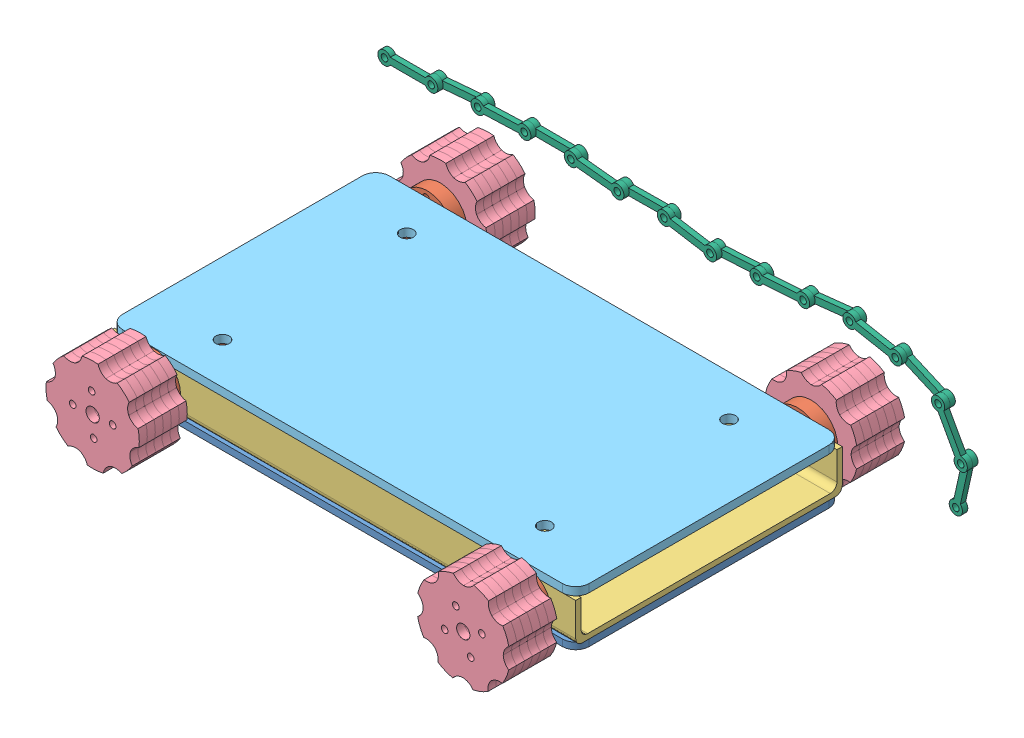
SolidWorks assembly robot, configuration Default. Lengths in mm.
Overall size (444.12 104.35 322.3).
44 component instances, 6 part files, 80 mates.
Components (placement in the parent):
- base-1: base [Default] at (85.4392 139.2891 312.3541) x (0 0 1) z (0 1 0) size (200 350 5)
- shaft-1: shaft [Default] at (-39.5608 161.2891 308.8259) x (0.053064 -0.998591 0) z (0 0 1) size (40 40 225)
- shaft-2: shaft [Default] at (240.4392 161.2891 310.7666) x (0.371711 -0.928348 0) z (0 0 1) size (40 40 225)
- secondBase-1: secondBase [Default] at (-74.5608 144.2891 412.3541) x (0 0 -1) z (1 0 0) size (200 30 350)
- belt-1: belt [Default] at (-39.5608 161.2891 423.8259) x (0.053064 -0.998591 0) z (0 0 1) size (70 70 6)
- belt-2: belt [Default] at (240.4392 161.2891 425.7666) x (0.371711 -0.928348 0) z (0 0 1) size (70 70 6)
- belt-3: belt [Default] at (-39.5608 161.2891 192.8259) x (-0.998591 -0.053064 0) z (0 0 1) size (70 70 6)
- belt-4: belt [Default] at (240.4392 161.2891 194.7666) x (0.371711 -0.928348 0) z (0 0 1) size (70 70 6)
- belt-5: belt [Default] at (-39.5608 161.2891 180.8259) x (-0.998591 -0.053064 0) z (0 0 1) size (70 70 6)
- belt-6: belt [Default] at (-39.5608 161.2891 186.8259) x (-0.998591 -0.053064 0) z (0 0 1) size (70 70 6)
- belt-7: belt [Default] at (-39.5608 161.2891 168.8259) x (0.053064 -0.998591 0) z (0 0 1) size (70 70 6)
- belt-8: belt [Default] at (-39.5608 161.2891 174.8259) x (-0.998591 -0.053064 0) z (0 0 1) size (70 70 6)
- belt-9: belt [Default] at (240.4392 161.2891 188.7666) x (-0.928348 -0.371711 0) z (0 0 1) size (70 70 6)
- belt-10: belt [Default] at (240.4392 161.2891 182.7666) x (-0.928348 -0.371711 0) z (0 0 1) size (70 70 6)
- belt-11: belt [Default] at (240.4392 161.2891 176.7666) x (-0.928348 -0.371711 0) z (0 0 1) size (70 70 6)
- belt-12: belt [Default] at (240.4392 161.2891 170.7666) x (-0.928348 -0.371711 0) z (0 0 1) size (70 70 6)
- belt-13: belt [Default] at (240.4392 161.2891 431.7666) x (0.371711 -0.928348 0) z (0 0 1) size (70 70 6)
- belt-14: belt [Default] at (240.4392 161.2891 437.7666) x (0.371711 -0.928348 0) z (0 0 1) size (70 70 6)
- belt-15: belt [Default] at (240.4392 161.2891 443.7666) x (0.371711 -0.928348 0) z (0 0 1) size (70 70 6)
- belt-16: belt [Default] at (240.4392 161.2891 449.7666) x (0.371711 -0.928348 0) z (0 0 1) size (70 70 6)
- belt-17: belt [Default] at (-39.5608 161.2891 429.8259) x (0.053064 -0.998591 0) z (0 0 1) size (70 70 6)
- belt-18: belt [Default] at (-39.5608 161.2891 435.8259) x (-0.998591 -0.053064 0) z (0 0 1) size (70 70 6)
- belt-19: belt [Default] at (-39.5608 161.2891 441.8259) x (0.053064 -0.998591 0) z (0 0 1) size (70 70 6)
- belt-20: belt [Default] at (-39.5608 161.2891 447.8259) x (0.053064 -0.998591 0) z (0 0 1) size (70 70 6)
- belt-21: belt [Default] at (-39.5608 161.2891 453.8259) x (0.053064 -0.998591 0) z (0 0 1) size (70 70 6)
- belt-22: belt [Default] at (240.4392 161.2891 455.7666) x (0.371711 -0.928348 0) z (0 0 1) size (70 70 6)
- belt-23: belt [Default] at (240.4392 161.2891 164.7666) x (-0.928348 -0.371711 0) z (0 0 1) size (70 70 6)
- belt-24: belt [Default] at (-39.5608 161.2891 162.8259) x (0.053064 -0.998591 0) z (0 0 1) size (70 70 6)
- top-1: top [Default] at (100.4392 180.2891 312.3541) x (0 0 -1) z (0 -1 0) size (200 350 6)
- chain-1: chain [Default] at (-225.8396 157.0049 133.5416) size (444.12 97.37 8)
  - chainPart-1: chainPart [Default] at (92.9067 33.2306 9.9294) size (45 10 4)
  - chainPart-2: chainPart [Default] at (127.9067 33.2306 5.9294) x (0.99643 0.084419 0) z (0 0 1) size (45 10 4)
  - chainPart-3: chainPart [Default] at (162.7817 36.1852 9.9294) x (0.999358 0.03582 0) z (0 0 1) size (45 10 4)
  - chainPart-4: chainPart [Default] at (197.7593 37.4389 5.9294) x (0.999994 -0.003474 0) z (0 0 1) size (45 10 4)
  - chainPart-5: chainPart [Default] at (232.7591 37.3173 9.9294) x (0.994631 -0.103489 0) z (0 0 1) size (45 10 4)
  - chainPart-6: chainPart [Default] at (267.5711 33.6952 5.9294) x (0.999959 0.009082 0) z (0 0 1) size (45 10 4)
  - chainPart-7: chainPart [Default] at (302.5697 34.0131 9.9294) x (0.986781 -0.162057 0) z (0 0 1) size (45 10 4)
  - chainPart-8: chainPart [Default] at (337.107 28.3411 5.9294) x (0.99823 0.059469 0) z (0 0 1) size (45 10 4)
  - chainPart-9: chainPart [Default] at (372.0451 30.4225 9.9294) x (0.997633 0.06876 0) z (0 0 1) size (45 10 4)
  - chainPart-10: chainPart [Default] at (406.9623 32.8291 5.9294) x (0.99408 0.108649 0) z (0 0 1) size (45 10 4)
  - chainPart-11: chainPart [Default] at (441.7551 36.6318 9.9294) x (0.982626 -0.185597 0) z (0 0 1) size (45 10 4)
  - chainPart-12: chainPart [Default] at (476.147 30.1359 5.9294) x (0.916872 -0.399181 0) z (0 0 1) size (45 10 4)
  - chainPart-13: chainPart [Default] at (508.2375 16.1646 9.9294) x (0.48532 -0.874336 0) z (0 0 1) size (45 10 4)
  - chainPart-14: chainPart [Default] at (525.2237 -14.4372 5.9294) x (-0.217955 -0.975959 0) z (0 0 1) size (45 10 4)
Mates (geometry in assembly coordinates):
- Coincident1: coincident anti-aligned: plane of base-1 through (85.4392 144.2891 312.3541) normal (0 1 0); plane of secondBase-1 through (275.4392 144.2891 412.3541) normal (0 -1 0)
- Coincident2: coincident aligned: plane of base-1 through (-74.5608 144.2891 412.3541) normal (-1 0 0); plane of secondBase-1 through (-74.5608 144.2891 412.3541) normal (-1 0 0)
- Coincident3: coincident aligned: plane of base-1 through (275.4392 144.2891 212.3541) normal (0 0 -1); plane of secondBase-1 through (275.4392 174.2891 212.3541) normal (0 0 -1)
- Concentric1: concentric anti-aligned: cylinder of shaft-1 through (-39.5608 161.2891 208.8259) axis (0 0 1) radius 5; cylinder of secondBase-1 through (-39.5608 161.2891 512.3541) axis (0 0 -1) radius 5
- Concentric2: concentric anti-aligned: cylinder of shaft-2 through (240.4392 161.2891 210.7666) axis (0 0 1) radius 5; circle of secondBase-1
- Coincident4: coincident anti-aligned: cylinder of shaft-1 through (-24.5819 162.0851 423.8259) axis (0 0 -1) radius 2.5; circle of belt-1
- Coincident5: coincident anti-aligned: plane of shaft-1 through (-39.5608 161.2891 423.8259) normal (0 0 1); plane of belt-1 through (-39.5608 161.2891 423.8259) normal (0 0 -1)
- Concentric3: concentric aligned: cylinder of shaft-1 through (-39.5608 161.2891 423.8259) axis (0 0 -1) radius 20; cylinder of belt-1 through (-39.5608 161.2891 429.8259) axis (0 0 -1) radius 5
- Coincident6: coincident anti-aligned: plane of shaft-2 through (240.4392 161.2891 425.7666) normal (0 0 1); plane of belt-2 through (240.4392 161.2891 425.7666) normal (0 0 -1)
- Coincident7: coincident anti-aligned: cylinder of shaft-2 through (254.3644 166.8648 425.7666) axis (0 0 -1) radius 2.5; circle of belt-2
- Concentric4: concentric aligned: cylinder of shaft-2 through (240.4392 161.2891 425.7666) axis (0 0 -1) radius 20; cylinder of belt-2 through (240.4392 161.2891 431.7666) axis (0 0 -1) radius 5
- Concentric5: concentric aligned: cylinder of shaft-1 through (-39.5608 161.2891 198.8259) axis (0 0 1) radius 20; circle of belt-3
- Concentric6: concentric anti-aligned: cylinder of shaft-1 through (-38.7648 146.3103 198.8259) axis (0 0 1) radius 2.5; cylinder of belt-3 through (-38.7648 146.3103 198.8259) axis (0 0 -1) radius 2.5
- Coincident8: coincident anti-aligned: plane of shaft-1 through (-39.5608 161.2891 198.8259) normal (0 0 -1); plane of belt-3 through (-39.5608 161.2891 198.8259) normal (0 0 1)
- Concentric7: concentric anti-aligned: cylinder of shaft-2 through (240.4392 161.2891 200.7666) axis (0 0 1) radius 20; cylinder of belt-4 through (240.4392 161.2891 200.7666) axis (0 0 -1) radius 5
- Coincident9: coincident aligned: circle of shaft-2; cylinder of belt-4 through (254.3644 166.8648 200.7666) axis (0 0 -1) radius 2.5
- Coincident10: coincident anti-aligned: plane of shaft-2 through (240.4392 161.2891 200.7666) normal (0 0 -1); plane of belt-4 through (240.4392 161.2891 200.7666) normal (0 0 1)
- Coincident11: coincident anti-aligned: plane of belt-3 through (-39.5608 161.2891 192.8259) normal (0 0 -1); plane of belt-6 through (-39.5608 161.2891 192.8259) normal (0 0 1)
- Concentric8: concentric aligned: cylinder of shaft-1 through (-39.5608 161.2891 198.8259) axis (0 0 1) radius 20; circle of belt-6
- Coincident13: coincident aligned: cylinder of shaft-1 through (-38.7648 146.3103 198.8259) axis (0 0 1) radius 2.5; circle of belt-6
- Coincident14: coincident anti-aligned: plane of belt-5 through (-39.5608 161.2891 186.8259) normal (0 0 1); plane of belt-6 through (-39.5608 161.2891 186.8259) normal (0 0 -1)
- Concentric9: concentric aligned: cylinder of belt-5 through (-39.5608 161.2891 186.8259) axis (0 0 -1) radius 5; cylinder of belt-6 through (-39.5608 161.2891 192.8259) axis (0 0 -1) radius 5
- Concentric10: concentric anti-aligned: cylinder of shaft-1 through (-38.7648 146.3103 198.8259) axis (0 0 1) radius 2.5; cylinder of belt-5 through (-38.7648 146.3103 186.8259) axis (0 0 -1) radius 2.5
- Coincident15: coincident anti-aligned: plane of belt-5 through (-39.5608 161.2891 180.8259) normal (0 0 -1); plane of belt-8 through (-39.5608 161.2891 180.8259) normal (0 0 1)
- Concentric11: concentric anti-aligned: cylinder of shaft-1 through (-39.5608 161.2891 198.8259) axis (0 0 1) radius 20; cylinder of belt-8 through (-39.5608 161.2891 180.8259) axis (0 0 -1) radius 5
- Concentric12: concentric anti-aligned: cylinder of shaft-1 through (-24.5819 162.0851 198.8259) axis (0 0 1) radius 2.5; cylinder of belt-8 through (-24.5819 162.0851 180.8259) axis (0 0 -1) radius 2.5
- Concentric13: concentric aligned: cylinder of belt-7 through (-39.5608 161.2891 174.8259) axis (0 0 -1) radius 5; cylinder of belt-8 through (-39.5608 161.2891 180.8259) axis (0 0 -1) radius 5
- Coincident17: coincident anti-aligned: plane of belt-7 through (-39.5608 161.2891 174.8259) normal (0 0 1); plane of belt-8 through (-39.5608 161.2891 174.8259) normal (0 0 -1)
- Coincident18: coincident aligned: cylinder of shaft-1 through (-24.5819 162.0851 198.8259) axis (0 0 1) radius 2.5; circle of belt-7
- Coincident19: coincident anti-aligned: circle of belt-4; cylinder of belt-9 through (240.4392 161.2891 194.7666) axis (0 0 -1) radius 5
- Concentric14: concentric anti-aligned: cylinder of shaft-2 through (254.3644 166.8648 200.7666) axis (0 0 1) radius 2.5; cylinder of belt-9 through (254.3644 166.8648 194.7666) axis (0 0 -1) radius 2.5
- Coincident20: coincident anti-aligned: plane of belt-4 through (240.4392 161.2891 194.7666) normal (0 0 -1); plane of belt-9 through (240.4392 161.2891 194.7666) normal (0 0 1)
- Concentric15: concentric aligned: cylinder of belt-9 through (240.4392 161.2891 194.7666) axis (0 0 -1) radius 5; cylinder of belt-10 through (240.4392 161.2891 188.7666) axis (0 0 -1) radius 5
- Concentric16: concentric aligned: cylinder of belt-9 through (254.3644 166.8648 194.7666) axis (0 0 -1) radius 2.5; cylinder of belt-10 through (254.3644 166.8648 188.7666) axis (0 0 -1) radius 2.5
- Coincident21: coincident anti-aligned: plane of belt-9 through (240.4392 161.2891 188.7666) normal (0 0 -1); plane of belt-10 through (240.4392 161.2891 188.7666) normal (0 0 1)
- Concentric17: concentric anti-aligned: cylinder of shaft-2 through (240.4392 161.2891 200.7666) axis (0 0 1) radius 20; cylinder of belt-11 through (240.4392 161.2891 182.7666) axis (0 0 -1) radius 5
- Concentric18: concentric anti-aligned: cylinder of shaft-2 through (254.3644 166.8648 200.7666) axis (0 0 1) radius 2.5; cylinder of belt-11 through (254.3644 166.8648 182.7666) axis (0 0 -1) radius 2.5
- Concentric19: concentric anti-aligned: cylinder of shaft-2 through (254.3644 166.8648 200.7666) axis (0 0 1) radius 2.5; cylinder of belt-12 through (254.3644 166.8648 176.7666) axis (0 0 -1) radius 2.5
- Concentric20: concentric aligned: cylinder of belt-10 through (240.4392 161.2891 188.7666) axis (0 0 -1) radius 5; cylinder of belt-12 through (240.4392 161.2891 176.7666) axis (0 0 -1) radius 5
- Coincident23: coincident anti-aligned: plane of belt-10 through (240.4392 161.2891 182.7666) normal (0 0 -1); plane of belt-11 through (240.4392 161.2891 182.7666) normal (0 0 1)
- Coincident24: coincident anti-aligned: plane of belt-11 through (240.4392 161.2891 176.7666) normal (0 0 -1); plane of belt-12 through (240.4392 161.2891 176.7666) normal (0 0 1)
- Concentric21: concentric aligned: cylinder of belt-2 through (240.4392 161.2891 431.7666) axis (0 0 -1) radius 5; cylinder of belt-13 through (240.4392 161.2891 437.7666) axis (0 0 -1) radius 5
- Concentric22: concentric aligned: cylinder of shaft-2 through (254.3644 166.8648 425.7666) axis (0 0 -1) radius 2.5; cylinder of belt-13 through (254.3644 166.8648 437.7666) axis (0 0 -1) radius 2.5
- Coincident25: coincident anti-aligned: plane of belt-2 through (240.4392 161.2891 431.7666) normal (0 0 1); plane of belt-13 through (240.4392 161.2891 431.7666) normal (0 0 -1)
- Coincident26: coincident anti-aligned: plane of belt-13 through (240.4392 161.2891 437.7666) normal (0 0 1); plane of belt-14 through (240.4392 161.2891 437.7666) normal (0 0 -1)
- Concentric23: concentric aligned: cylinder of belt-13 through (254.3644 166.8648 437.7666) axis (0 0 -1) radius 2.5; cylinder of belt-14 through (254.3644 166.8648 443.7666) axis (0 0 -1) radius 2.5
- Concentric24: concentric aligned: cylinder of shaft-2 through (240.4392 161.2891 425.7666) axis (0 0 -1) radius 20; cylinder of belt-14 through (240.4392 161.2891 443.7666) axis (0 0 -1) radius 5
- Coincident27: coincident anti-aligned: plane of belt-14 through (240.4392 161.2891 443.7666) normal (0 0 1); plane of belt-15 through (240.4392 161.2891 443.7666) normal (0 0 -1)
- Concentric25: concentric aligned: cylinder of belt-14 through (240.4392 161.2891 443.7666) axis (0 0 -1) radius 5; cylinder of belt-15 through (240.4392 161.2891 449.7666) axis (0 0 -1) radius 5
- Coincident28: coincident anti-aligned: cylinder of shaft-2 through (254.3644 166.8648 425.7666) axis (0 0 -1) radius 2.5; circle of belt-15
- Concentric26: concentric aligned: cylinder of belt-15 through (240.4392 161.2891 449.7666) axis (0 0 -1) radius 5; cylinder of belt-16 through (240.4392 161.2891 455.7666) axis (0 0 -1) radius 5
- Coincident29: coincident anti-aligned: cylinder of belt-15 through (254.3644 166.8648 449.7666) axis (0 0 -1) radius 2.5; circle of belt-16
- Coincident30: coincident anti-aligned: plane of belt-15 through (240.4392 161.2891 449.7666) normal (0 0 1); plane of belt-16 through (240.4392 161.2891 449.7666) normal (0 0 -1)
- Concentric27: concentric aligned: cylinder of belt-1 through (-39.5608 161.2891 429.8259) axis (0 0 -1) radius 5; cylinder of belt-17 through (-39.5608 161.2891 435.8259) axis (0 0 -1) radius 5
- Concentric28: concentric aligned: cylinder of belt-1 through (-40.3568 176.268 429.8259) axis (0 0 -1) radius 2.5; cylinder of belt-17 through (-40.3568 176.268 435.8259) axis (0 0 -1) radius 2.5
- Coincident31: coincident anti-aligned: plane of belt-1 through (-39.5608 161.2891 429.8259) normal (0 0 1); plane of belt-17 through (-39.5608 161.2891 429.8259) normal (0 0 -1)
- Concentric29: concentric aligned: cylinder of shaft-1 through (-39.5608 161.2891 423.8259) axis (0 0 -1) radius 20; cylinder of belt-18 through (-39.5608 161.2891 441.8259) axis (0 0 -1) radius 5
- Coincident32: coincident anti-aligned: cylinder of shaft-1 through (-40.3568 176.268 423.8259) axis (0 0 -1) radius 2.5; circle of belt-18
- Coincident33: coincident anti-aligned: plane of belt-17 through (-39.5608 161.2891 435.8259) normal (0 0 1); plane of belt-18 through (-39.5608 161.2891 435.8259) normal (0 0 -1)
- Concentric30: concentric aligned: cylinder of belt-18 through (-39.5608 161.2891 441.8259) axis (0 0 -1) radius 5; cylinder of belt-19 through (-39.5608 161.2891 447.8259) axis (0 0 -1) radius 5
- Concentric31: concentric aligned: cylinder of belt-18 through (-40.3568 176.268 441.8259) axis (0 0 -1) radius 2.5; cylinder of belt-19 through (-40.3568 176.268 447.8259) axis (0 0 -1) radius 2.5
- Coincident34: coincident anti-aligned: plane of belt-18 through (-39.5608 161.2891 441.8259) normal (0 0 1); plane of belt-19 through (-39.5608 161.2891 441.8259) normal (0 0 -1)
- Concentric32: concentric aligned: cylinder of belt-19 through (-39.5608 161.2891 447.8259) axis (0 0 -1) radius 5; cylinder of belt-20 through (-39.5608 161.2891 453.8259) axis (0 0 -1) radius 5
- Concentric33: concentric aligned: cylinder of belt-19 through (-40.3568 176.268 447.8259) axis (0 0 -1) radius 2.5; cylinder of belt-20 through (-40.3568 176.268 453.8259) axis (0 0 -1) radius 2.5
- Coincident35: coincident anti-aligned: plane of belt-19 through (-39.5608 161.2891 447.8259) normal (0 0 1); plane of belt-20 through (-39.5608 161.2891 447.8259) normal (0 0 -1)
- Concentric34: concentric aligned: cylinder of belt-20 through (-39.5608 161.2891 453.8259) axis (0 0 -1) radius 5; cylinder of belt-21 through (-39.5608 161.2891 459.8259) axis (0 0 -1) radius 5
- Concentric35: concentric aligned: cylinder of shaft-1 through (-24.5819 162.0851 423.8259) axis (0 0 -1) radius 2.5; cylinder of belt-21 through (-24.5819 162.0851 459.8259) axis (0 0 -1) radius 2.5
- Coincident36: coincident anti-aligned: plane of belt-20 through (-39.5608 161.2891 453.8259) normal (0 0 1); plane of belt-21 through (-39.5608 161.2891 453.8259) normal (0 0 -1)
- Concentric36: concentric aligned: cylinder of belt-16 through (240.4392 161.2891 455.7666) axis (0 0 -1) radius 5; cylinder of belt-22 through (240.4392 161.2891 461.7666) axis (0 0 -1) radius 5
- Concentric37: concentric aligned: cylinder of belt-16 through (254.3644 166.8648 455.7666) axis (0 0 -1) radius 2.5; cylinder of belt-22 through (254.3644 166.8648 461.7666) axis (0 0 -1) radius 2.5
- Coincident37: coincident anti-aligned: plane of belt-16 through (240.4392 161.2891 455.7666) normal (0 0 1); plane of belt-22 through (240.4392 161.2891 455.7666) normal (0 0 -1)
- Concentric38: concentric aligned: cylinder of belt-7 through (-39.5608 161.2891 174.8259) axis (0 0 -1) radius 5; cylinder of belt-24 through (-39.5608 161.2891 168.8259) axis (0 0 -1) radius 5
- Concentric39: concentric anti-aligned: cylinder of shaft-1 through (-40.3568 176.268 198.8259) axis (0 0 1) radius 2.5; cylinder of belt-24 through (-40.3568 176.268 168.8259) axis (0 0 -1) radius 2.5
- Coincident38: coincident anti-aligned: plane of belt-7 through (-39.5608 161.2891 168.8259) normal (0 0 -1); plane of belt-24 through (-39.5608 161.2891 168.8259) normal (0 0 1)
- Concentric40: concentric aligned: cylinder of belt-12 through (240.4392 161.2891 176.7666) axis (0 0 -1) radius 5; cylinder of belt-23 through (240.4392 161.2891 170.7666) axis (0 0 -1) radius 5
- Concentric41: concentric aligned: cylinder of belt-12 through (254.3644 166.8648 176.7666) axis (0 0 -1) radius 2.5; cylinder of belt-23 through (254.3644 166.8648 170.7666) axis (0 0 -1) radius 2.5
- Coincident39: coincident anti-aligned: plane of belt-12 through (240.4392 161.2891 170.7666) normal (0 0 -1); plane of belt-23 through (240.4392 161.2891 170.7666) normal (0 0 1)
- Coincident42: coincident aligned: plane of secondBase-1 through (275.4392 174.2891 412.3541) normal (0 0 1); plane of top-1 through (-74.5608 174.2891 412.3541) normal (0 0 1)
- Coincident43: coincident aligned: plane of base-1 through (275.4392 144.2891 412.3541) normal (1 0 0); plane of top-1 through (275.4392 174.2891 412.3541) normal (1 0 0)
- Coincident44: coincident anti-aligned: plane of secondBase-1 through (275.4392 174.2891 412.3541) normal (0 1 0); plane of top-1 through (100.4392 174.2891 312.3541) normal (0 -1 0)
